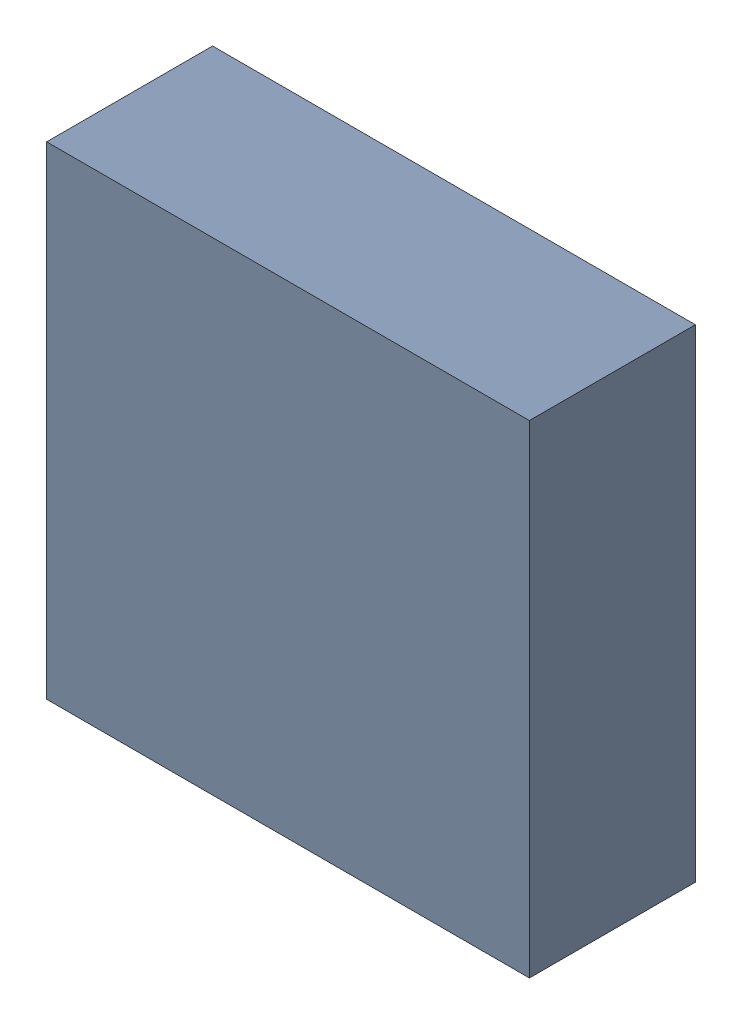
SolidWorks assembly U302_2PCB, configuration Default. Lengths in mm.
Overall size (3.2 3.2 1.1).
2 component instances, 1 part files, 0 mates.
Components (placement in the parent):
- 846484240-1: 846484240 [Default] at (142 89.3 0) size (3.2 3.2 1.1)
  - Extruded_11-1: Extruded_11 [Default] at origin size (3.2 3.2 1.1)
